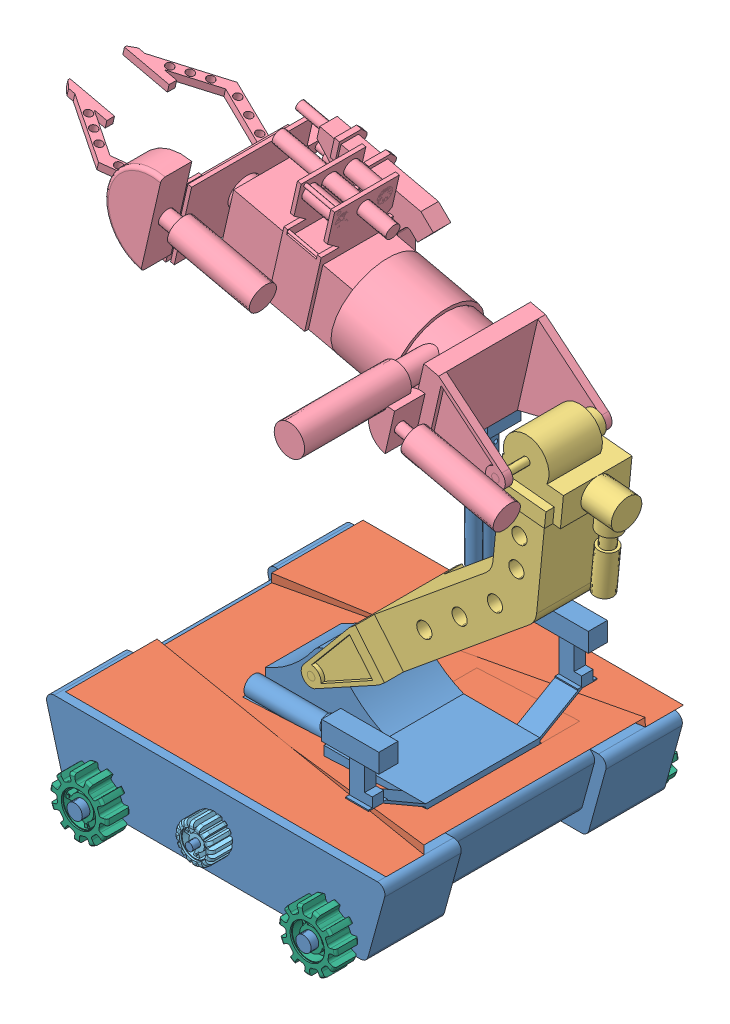
SolidWorks assembly final ROV model, configuration Default. Lengths in mm.
Overall size (748.23 806.35 480).
10 component instances, 6 part files, 12 mates.
Components (placement in the parent):
- base-1: base [Default] at (244.8882 235.5554 101.1832) size (443.72 344.84 475)
- surface f-2: surface f [Default] at (48.0313 235.5554 295.9389) x (0 0 1) z (-0.999657 -0.026181 0) size (390 11 420)
- lower hand-2: lower hand [Default] at (338.3353 377.5875 246.1832) x (0.771624 0.636079 0) z (0 0 -1) size (496.89 183.69 145)
- upper limb-2: upper limb [Default] at (501.5688 661.2831 381.1832) x (-0.974874 0.222757 0) z (0 0 -1) size (651.52 171.43 340)
- bigger wheel-1: bigger wheel [Default] at (244.8882 174.7142 101.1832) x (-0.887144 -0.461493 0) z (0 0 -1) size (50.27 50.27 30.6)
- smaller wheel-2: smaller wheel [Default] at (394.8882 149.7142 101.1832) x (-0.946421 -0.322934 0) z (0 0 -1) size (75.92 75.33 30)
- bigger wheel-2: bigger wheel [Default] at (244.8882 186.6 491.1832) x (0.777871 0.628424 0) z (0 0 1) size (50.27 50.27 30.6)
- smaller wheel-3: smaller wheel [Default] at (94.8882 151.6 491.1832) x (0.197424 0.980318 0) z (0 0 1) size (75.92 75.33 30)
- smaller wheel-4: smaller wheel [Default] at (394.8882 151.6 491.1832) x (-0.841329 0.540523 0) z (0 0 1) size (75.92 75.33 30)
- smaller wheel-5: smaller wheel [Default] at (94.9 149.7142 101.1832) x (0.114967 0.993369 0) z (0 0 -1) size (75.92 75.33 30)
Mates (geometry in assembly coordinates):
- Coincident12: coincident: line of assembly; line of assembly; line of base-1 through (48.0313 235.5554 391.1832) axis (0 0 -1); line of surface f-2 through (48.0313 235.5554 220.9389) axis (0 0 1)
- Parallel9: parallel: line of assembly; line of assembly; line of base-1 through (456.7488 235.5554 101.1832) axis (-1 0 0); line of surface f-2 through (467.8873 246.5516 100.9389) axis (-1 0 0)
- Parallel16: parallel: line of assembly; line of assembly; line of base-1 through (456.745 235.5554 491.1832) axis (-1 0 0); line of surface f-2 through (47.7433 246.5516 490.9389) axis (1 0 0)
- Lock1: lock: unknown of base-1; unknown of surface f-2
- Coincident17: coincident: circle of assembly; circle of assembly; circle of base-1; circle of smaller wheel-2
- Coincident18: coincident: circle of assembly; circle of assembly; circle of base-1; circle of bigger wheel-1
- Coincident19: coincident: circle of base-1; circle of ?
- Coincident20: coincident: circle of base-1; circle of ?
- Coincident21: coincident: circle of base-1; circle of ?
- Coincident22: coincident: circle of assembly; circle of assembly; circle of base-1; circle of smaller wheel-5
- Coincident24: coincident: circle of base-1; circle of ?
- Coincident25: coincident: circle of ?; circle of ?
